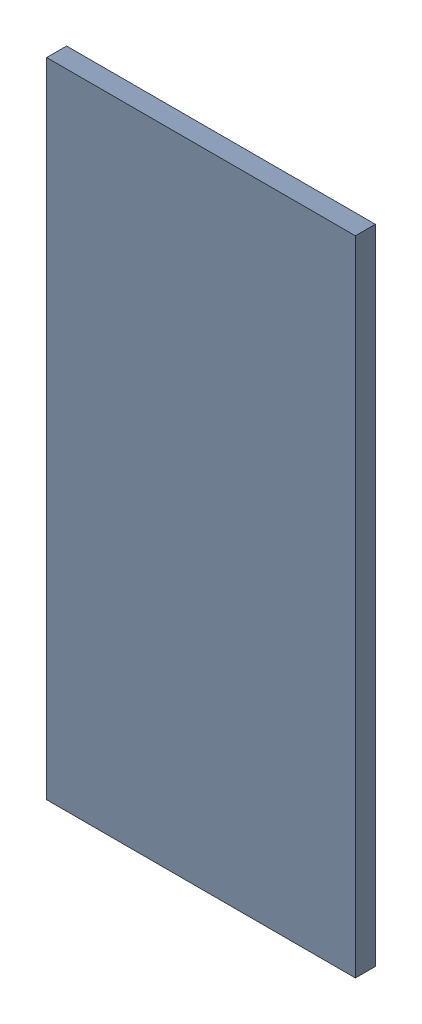
SolidWorks assembly Pad ADXL345-13(23mm,55.903mm) on Top Layer, configuration Predeterminado. Lengths in mm.
Overall size (0.55 1.15 0.04).
2 component instances, 1 part files, 0 mates.
Components (placement in the parent):
- Pad ADXL345-13(23mm,55.903mm) on Top Layer-1-1: Pad ADXL345-13(23mm,55.903mm) on Top Layer-1 [Predeterminado] at (-68.317 -44.187 -0.0457) size (0.55 1.15 0.04)
  - Pad ADXL345-13(23mm,55.903mm) on Top Layer-Part-1-1: Pad ADXL345-13(23mm,55.903mm) on Top Layer-Part-1 [Predeterminado] at origin size (0.55 1.15 0.04)
